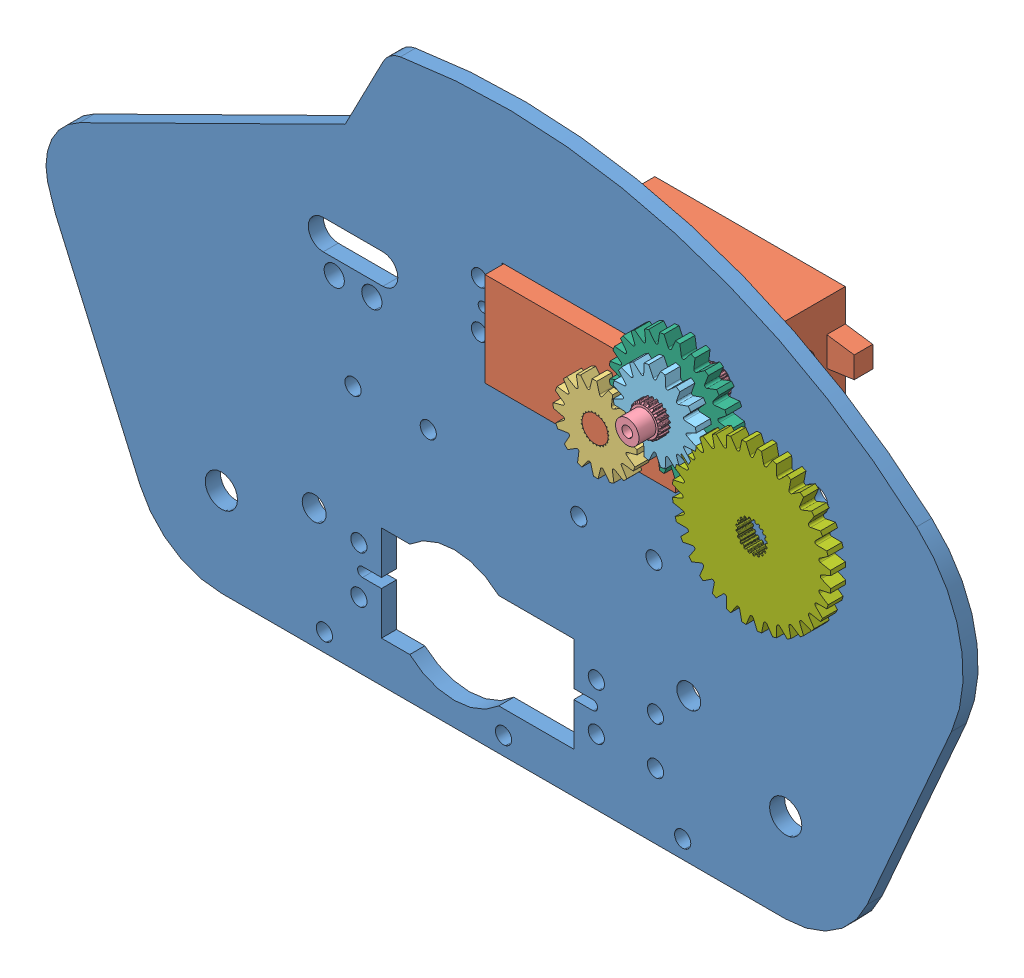
SolidWorks assembly Arm Drive, configuration Default. Lengths in mm.
Overall size (195.06 119.68 51.83).
7 component instances, 7 part files, 12 mates.
Components (placement in the parent):
- drive plate_arm-1: drive plate_arm [Default] at origin size (195.06 119.68 3.2)
- Servo_ContRotation-1: Servo_ContRotation [Default] at (59.8915 90.5358 -2.5) x (0 -1 0) z (0 0 1) size (20 55.5 42.8)
- 16T Gear_Futaba Spline-1: 16T Gear_Futaba Spline [Default] at (89.9915 80.5358 10.5017) x (0.541997 0.84038 0) z (0 0 1) size (17.68 17.68 3.2)
- 3x_Custom Axle w-ends-1: 3x_Custom Axle w-ends [Default] at (105.8603 92.4374 11.3665) size (6.65 6.65 22.73)
- 16T Gear_Custom Axle-1: 16T Gear_Custom Axle [Default] at (105.8603 92.4374 15.3023) size (17.68 17.68 3.2)
- 24T Gear_Custom Axle-1: 24T Gear_Custom Axle [Default] at (105.8603 92.4374 12.1019) size (25.67 25.67 3.2)
- 32T Gear_Custom Axle-2: 32T Gear_Custom Axle [Default] at (126.4745 80.5358 15.3023) size (33.64 33.64 3.2)
Mates (geometry in assembly coordinates):
- Coincident1: coincident: plane of drive plate_arm-1 through (128.1135 64.0417 0) normal (0 0 -1); plane of Servo_ContRotation-1 through (59.8915 90.5358 0) normal (0 0 1)
- Concentric1: concentric: cylinder of drive plate_arm-1 through (105.3915 75.5358 48.8646) axis (0 0 -1) radius 1.7272; cylinder of Servo_ContRotation-1 through (105.3915 75.5358 0) axis (0 0 -1) radius 2.25
- Concentric2: concentric: cylinder of drive plate_arm-1 through (54.8915 85.5358 48.8646) axis (0 0 -1) radius 1.7272; cylinder of Servo_ContRotation-1 through (54.8915 85.5358 0) axis (0 0 -1) radius 2.25
- Coincident2: coincident: plane of Servo_ContRotation-1 through (89.9915 80.5358 13.7021) normal (0 0 1); plane of 16T Gear_Futaba Spline-1 through (89.9915 80.5358 13.7021) normal (0 0 1)
- Concentric3: concentric: cylinder of Servo_ContRotation-1 through (89.9915 80.5358 13.7021) axis (0 0 -1) radius 2.794; circle of 16T Gear_Futaba Spline-1
- Concentric4: concentric: cylinder of drive plate_arm-1 through (105.8603 92.4374 48.8646) axis (0 0 -1) radius 2.54; cylinder of 3x_Custom Axle w-ends-1 through (105.8603 92.4374 22.733) axis (0 0 -1) radius 2.5019
- Coincident3: coincident: plane of drive plate_arm-1 through (128.1135 64.0417 0) normal (0 0 -1); plane of 3x_Custom Axle w-ends-1 through (105.8603 92.4374 0) normal (0 0 -1)
- Concentric5: concentric: cylinder of 3x_Custom Axle w-ends-1 through (105.8603 92.4374 22.733) axis (0 0 -1) radius 2.5019; circle of 16T Gear_Custom Axle-1
- Concentric6: concentric: cylinder of 3x_Custom Axle w-ends-1 through (105.8603 92.4374 22.733) axis (0 0 -1) radius 2.5019; circle of 24T Gear_Custom Axle-1
- Coincident5: coincident: plane of 16T Gear_Futaba Spline-1 through (89.9915 80.5358 13.7021) normal (0 0 1); plane of 24T Gear_Custom Axle-1 through (105.8603 92.4374 13.7021) normal (0 0 1)
- Coincident6: coincident: plane of 16T Gear_Custom Axle-1 through (105.8603 92.4374 13.7021) normal (0 0 -1); plane of 32T Gear_Custom Axle-2 through (126.4745 80.5358 13.7021) normal (0 0 -1)
- Coincident7: coincident: plane of 16T Gear_Custom Axle-1 through (105.8603 92.4374 13.7021) normal (0 0 -1); plane of 24T Gear_Custom Axle-1 through (105.8603 92.4374 13.7021) normal (0 0 1)
